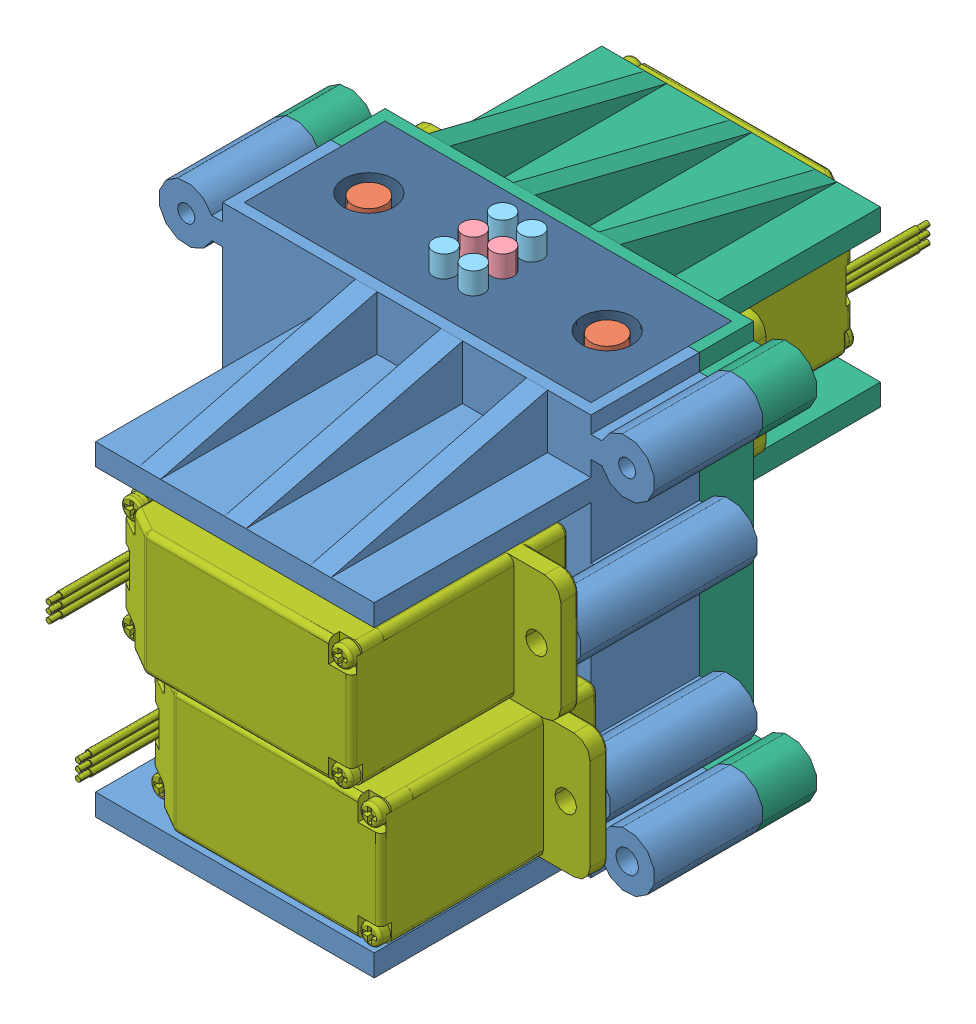
SolidWorks assembly Tête d'impression, configuration eclater. Lengths in mm.
Overall size (45.79 42 70.8).
20 component instances, 10 part files, 39 mates.
Components (placement in the parent):
- bati part 1-1: bati part 1 [Défaut] at (-49.0706 -11.5721 7.5)
- colone de guidage-1: colone de guidage [Défaut] at (-43.697 22.4279 1.3629) x (0.417627 0 -0.908618) z (0.908618 0 0.417627)
- colone de guidage-2: colone de guidage [Défaut] at (-21.8781 22.4279 1.2641) x (0.538353 0 -0.842719) z (0.842719 0 0.538353)
- Plaque Rappel-1: Plaque Rappel [Défaut] at (-32.0706 17.9279 0) x (0 0 1) z (0 -1 0)
- Pointeau Long-1: Pointeau Long [Défaut] at (-32.0706 20.9279 0) x (0 0 1) z (0 -1 0)
- Pointeau Long-2: Pointeau Long [Défaut] at (-32.0706 20.9279 0) x (0 0 -1) z (0 -1 0)
- Pointeau Court-1: Pointeau Court [Défaut] at (-32.0706 21.9279 0) x (0 0 -1) z (0 -1 0)
- Pointeau Court-2: Pointeau Court [Défaut] at (-32.0706 21.9279 -5.4) x (0 0 1) z (0 -1 0)
- Pointeau Court-3: Pointeau Court [Défaut] at (-32.0706 21.9279 5.4) x (0 0 -1) z (0 -1 0)
- Pointeau Court-4: Pointeau Court [Défaut] at (-32.0706 21.9279 0) x (0 0 1) z (0 -1 0)
- bati part 2-1: bati part 2 [Défaut] at (-15.0706 -9.5721 -7.5) x (-1 0 0) z (0 1 0)
- Servomoteur-1: Servomoteur [Défaut] at (-49.8958 18.419 -27.4) x (0 -1 0) z (-1 0 0)
- Servomoteur-2: Servomoteur [Défaut] at (-14.2454 18.419 27.4) x (0 -1 0) z (1 0 0)
- Servomoteur-3: Servomoteur [Défaut] at (-14.2454 4.419 24.7) x (0 -1 0) z (1 0 0)
- Came-1: Came [Défaut] at (-32.1295 6.5039 -5.6) x (0.016168 0.999869 0) z (0 0 1)
- Came-2: Came [Défaut] at (-31.7263 18.691 5.6) x (-0.062946 -0.998017 0) z (0 0 -1)
- Ressort de compression 5,3x0,5 - L=12 - 10 spires-1: Ressort de compression 5,3x0,5 - L=12 - 10 spires [Défaut] at (-43.243 22.4279 -0.6267) x (0 -1 0) z (-0.940562 0 -0.339622)
- Ressort de compression 5,3x0,5 - L=12 - 10 spires-2: Ressort de compression 5,3x0,5 - L=12 - 10 spires [Défaut] at (-21.2059 22.4279 -0.6357) x (0 -1 0) z (0.238492 0 0.971145)
- Came-3: Came [Défaut] at (-32.0129 4.703 -8.3) x (-0.002944 -0.999996 0) z (0 0 1)
- Sauvegarde de plaque de guidage version plastique V2-1: Sauvegarde de plaque de guidage version plastique V2 [Défaut] at (-48.0706 25.4279 -6.5) x (1 0 0) z (0 -1 0)
Mates (geometry in assembly coordinates):
- Coaxiale5: concentric anti-aligned: cylinder of colone de guidage (+fixation)-2 through (-21.0706 -14.5721 0) axis (0 -1 0) radius 2; cylinder of Plaque Rappel Ressort-1 through (-21.0706 4.4279 0) axis (0 1 0) radius 2.1
- Coaxiale6: concentric anti-aligned: cylinder of colone de guidage (+fixation)-1 through (-43.0706 -14.5721 0) axis (0 -1 0) radius 2; cylinder of Plaque Rappel Ressort-1 through (-43.0706 4.4279 0) axis (0 1 0) radius 2.1
- Parallèle1: parallel aligned: plane of Plaque Rappel Ressort-1 through (-47.0706 20.4279 -5.5) normal (0 0 -1); plane of Poinçon Long-2 through (-29.2007 31.9279 -1.3) normal (0 0 -1)
- Parallèle2: parallel aligned: plane of Plaque Rappel Ressort-1 through (-47.0706 20.4279 -5.5) normal (0 0 -1); plane of Poinçon Long-1 through (-34.9404 31.9279 -1.3) normal (0 0 -1)
- Coïncidente12: coincident anti-aligned: plane of Plaque Rappel Ressort-1 through (-47.0706 4.4279 38.6059) normal (0 -1 0); plane of Poinçon Long-2 through (-30.7206 4.4279 0) normal (0 1 0)
- Coïncidente13: coincident anti-aligned: plane of Plaque Rappel Ressort-1 through (-47.0706 4.4279 38.6059) normal (0 -1 0); plane of Poinçon Long-1 through (-33.4206 4.4279 0) normal (0 1 0)
- Parallèle3: parallel aligned: plane of Plaque Rappel Ressort-1 through (-47.0706 20.4279 -5.5) normal (0 0 -1); plane of Poinçon Court-2 through (-34.9404 32.9279 -4) normal (0 0 -1)
- Parallèle4: parallel aligned: plane of Plaque Rappel Ressort-1 through (-47.0706 20.4279 -5.5) normal (0 0 -1); plane of Poinçon Court-1 through (-32.0206 32.9279 -4) normal (0 0 -1)
- Parallèle5: parallel aligned: plane of Plaque Rappel Ressort-1 through (-47.0706 20.4279 -5.5) normal (0 0 -1); plane of Poinçon Court-4 through (-34.9404 32.9279 1.4) normal (0 0 -1)
- Parallèle6: parallel aligned: plane of Plaque Rappel Ressort-1 through (-47.0706 20.4279 -5.5) normal (0 0 -1); plane of Poinçon Court-3 through (-32.0206 32.9279 1.4) normal (0 0 -1)
- Coïncidente19: coincident anti-aligned: plane of Plaque Rappel Ressort-1 through (-32.0706 18.4279 0) normal (0 -1 0); plane of Poinçon Court-2 through (-33.4206 18.4279 -2.7) normal (0 1 0)
- Coïncidente20: coincident anti-aligned: plane of Plaque Rappel Ressort-1 through (-32.0706 18.4279 0) normal (0 -1 0); plane of Poinçon Court-1 through (-30.7206 18.4279 -2.7) normal (0 1 0)
- Coïncidente21: coincident anti-aligned: plane of Plaque Rappel Ressort-1 through (-32.0706 18.4279 0) normal (0 -1 0); plane of Poinçon Court-4 through (-33.4206 18.4279 2.7) normal (0 1 0)
- Coïncidente22: coincident aligned: plane of Plaque Rappel Ressort-1 through (-32.0706 18.4279 0) normal (0 -1 0); circle of Poinçon Court-3
- Coïncidente24: coincident aligned: plane of bati part 1-1 through (-49.0706 25.4279 7.5) normal (0 1 0); plane of bati part 2-1 through (-15.0706 25.4279 -11.5) normal (0 1 0)
- Coïncidente26: coincident anti-aligned: plane of bati part 1-1 through (-39.0706 4.4279 7.5) normal (0 -1 0); plane of BON SERVO-3 through (-42.3509 4.4279 13.7) normal (0 1 0)
- Distance3: distance = 0.8 mm aligned: plane of BON SERVO-3 through (-14.2706 3.737 -13.4217) normal (1 0 0); plane of bati part 1-1 through (-15.0706 -9.5721 7.5) normal (1 0 0)
- Coïncidente31: coincident anti-aligned: plane of bati part 1-1 through (-25.0706 18.4279 7.5) normal (0 -1 0); plane of BON SERVO-2 through (-37.0337 18.4279 -10.7217) normal (0 1 0)
- Distance5: distance = 0.8 mm aligned: plane of BON SERVO-2 through (-14.2706 17.737 -10.7217) normal (1 0 0); plane of bati part 1-1 through (-15.0706 -9.5721 7.5) normal (1 0 0)
- Coaxiale13: concentric anti-aligned: circle of BON SERVO-2; cylinder of Rotor Servo-1 through (-32.0309 12.6031 3.4) axis (0 0 1) radius 1.75
- Distance7: distance = 0.5 mm anti-aligned: plane of Rotor Servo-1 through (-32.0309 12.6031 5.9) normal (0 0 1); plane of BON SERVO-2 through (-32.0309 12.6031 6.4) normal (0 0 -1)
- Coïncidente37: coincident aligned: plane of Poinçon Court-3 through (-32.0206 32.9279 1.4) normal (0 0 -1); plane of Rotor Servo-1 through (-33.2807 12.6233 1.4) normal (0 0 -1)
- Coaxiale14: concentric anti-aligned: circle of BON SERVO-1; cylinder of Came-2 through (-32.1102 12.6031 -3.4) axis (0 0 -1) radius 1.75
- Distance8: distance = 0.5 mm anti-aligned: plane of BON SERVO-1 through (-32.1102 12.6031 -6.4) normal (0 0 1); plane of Rotor Servo-2 through (-32.1102 12.6031 -5.9) normal (0 0 -1)
- Coïncidente40: coincident anti-aligned: plane of bati part 2-1 through (-25.0706 18.4279 -11.5) normal (0 -1 0); plane of Servomoteur-1 through (-21.7902 18.4279 -16.4) normal (0 1 0)
- Distance9: distance = 0.8 mm aligned: plane of BON SERVO-1 through (-49.8706 17.737 10.7217) normal (-1 0 0); plane of bati part 2-1 through (-49.0706 25.4279 -7.5) normal (-1 0 0)
- Coïncidente42: coincident aligned: plane of Poinçon Court-2 through (-32.1206 32.9279 -1.4) normal (0 0 1); plane of Came-2 through (-33.3578 12.6817 -1.4) normal (0 0 1)
- Coaxiale15: concentric anti-aligned: cylinder of bati part 1-1 through (-21.0706 -11.5721 0) axis (0 1 0) radius 1.5; cylinder of colone de guidage (+fixation)-2 through (-21.0706 -14.5721 0) axis (0 -1 0) radius 3
- Coïncidente43: coincident anti-aligned: plane of bati part 1-1 through (-49.0706 -9.5721 7.5) normal (0 1 0); plane of colone de guidage (+fixation)-2 through (-22.6856 -9.5721 2.5282) normal (0 -1 0)
- Tangent7: tangent aligned: face of Plaque Rappel Ressort-1; cylinder of colone de guidage (+fixation)-1 through (-43.0706 -14.5721 0) axis (0 -1 0) radius 2
- Tangent8: tangent aligned: cylinder of colone de guidage-2 through (-21.0706 -14.5721 0) axis (0 -1 0) radius 2; edge_curve of Ressort de compression 5,3x0,5 - L=12 - 10 spires-2
- Coaxiale16: concentric anti-aligned: circle of BON SERVO-3; circle of Rotor Servo-3
- Distance10: distance = 0.5 mm anti-aligned: plane of Rotor Servo-3 through (-32.0309 -1.3969 3.2) normal (0 0 1); plane of BON SERVO-3 through (-32.0309 -1.3969 3.7) normal (0 0 -1)
- Coïncidente52: coincident aligned: plane of Poinçon Long-2 through (-29.2007 31.9279 -1.3) normal (0 0 -1); plane of Rotor Servo-3 through (-30.7809 -1.4006 -1.3) normal (0 0 -1)
- Coaxiale18: concentric anti-aligned: cylinder of colone de guidage-2 through (-21.0706 -14.5721 0) axis (0 -1 0) radius 1.5; cylinder of Sauvegarde de plaque de guidage version plastique V2-1 through (-21.0706 22.4279 0) axis (0 1 0) radius 2.3
- Coaxiale19: concentric anti-aligned: cylinder of colone de guidage-1 through (-43.0706 -14.5721 0) axis (0 -1 0) radius 1.5; cylinder of Sauvegarde de plaque de guidage version plastique V2-1 through (-43.0706 22.4279 0) axis (0 1 0) radius 2.3
- Coïncidente53: coincident anti-aligned: plane of bati part 1-1 through (-49.0706 22.4279 7.5) normal (0 1 0); plane of Sauvegarde de plaque de guidage version plastique V2-1 through (-48.0706 22.4279 -6.5) normal (0 -1 0)
- Coïncidente54: coincident anti-aligned: plane of bati part 2-1 through (-16.0706 22.4279 -2.5) normal (-1 0 0); plane of Sauvegarde de plaque de guidage version plastique V2-1 through (-16.0706 22.4279 -6.5) normal (1 0 0)
- Coïncidente55: coincident anti-aligned: plane of bati part 2-1 through (-16.0706 22.4279 -6.5) normal (0 0 1); plane of Sauvegarde de plaque de guidage version plastique V2-1 through (-48.0706 22.4279 -6.5) normal (0 0 -1)
